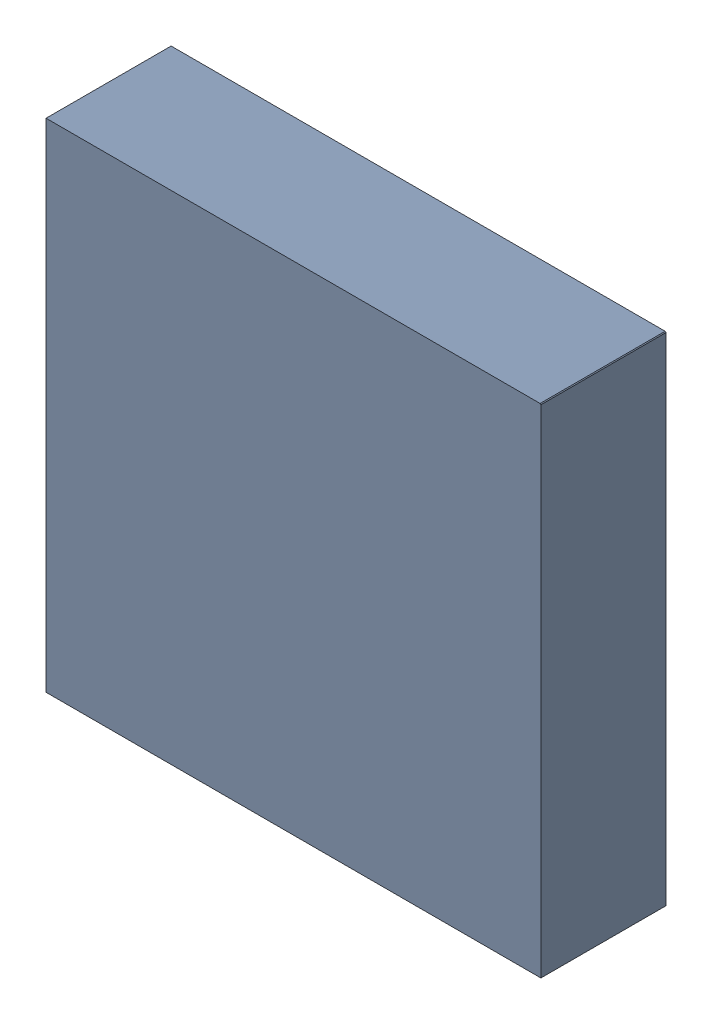
SolidWorks assembly U4, configuration 默认. Lengths in mm.
Overall size (3.17 3.19 0.82).
4 component instances, 2 part files, 0 mates.
Components (placement in the parent):
- 6641442208-1: 6641442208.stp [默认] at (4.4325 4.57 -2.7339) size (3.17 3.19 0.81)
  - Extruded-19-1: Extruded-19 [默认] at origin size (3.17 3.19 0.81)
- 6641440128-1: 6641440128 [默认] at (5.7448 3.3092 -2.7339) x (0 1 0) z (0 0 -1) size (0.2 0.2 0.01)
  - Cylinder-23-1: Cylinder-23 [默认] at origin size (0.2 0.2 0.01)
